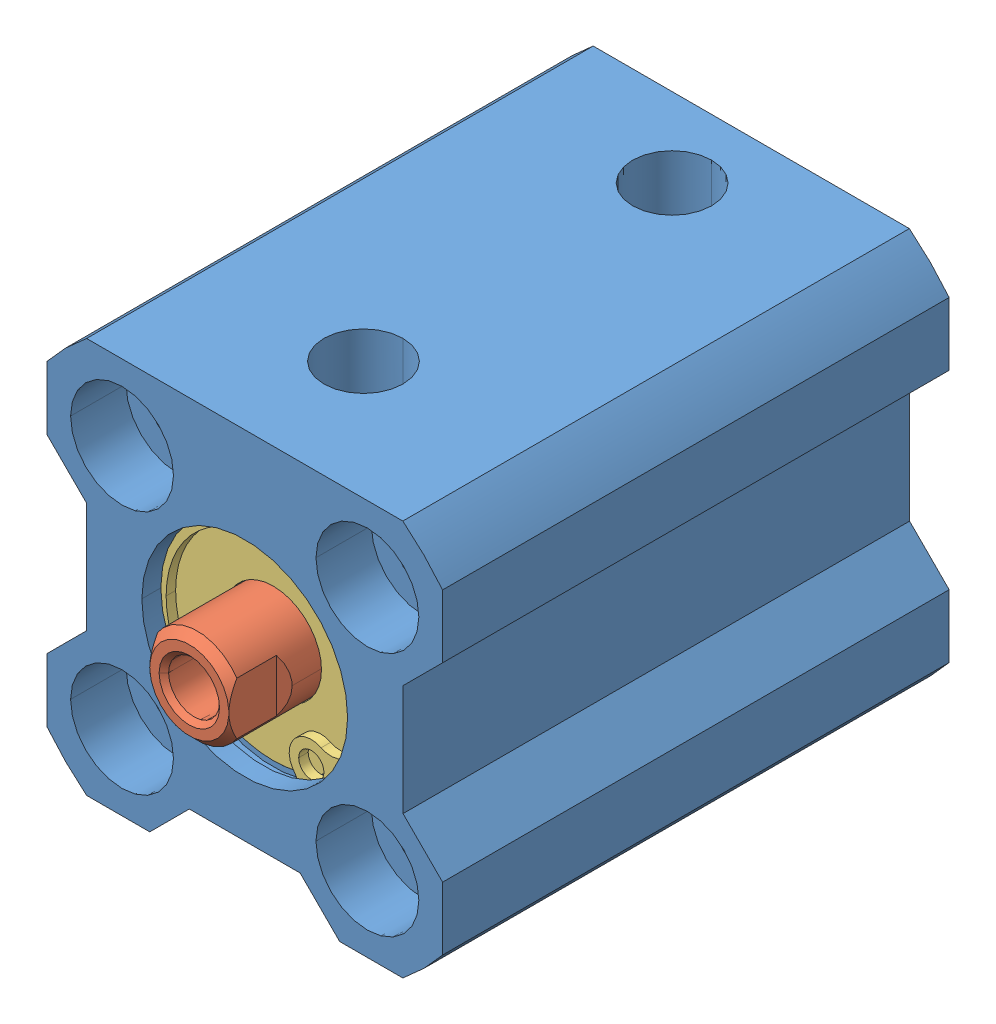
SolidWorks assembly NCQ2B12-15D, configuration Default. Lengths in mm.
Overall size (25 25 35.5).
4 component instances, 3 part files, 0 mates.
Components (placement in the parent):
- NCQ2B12-15D.STEP-1: NCQ2B12-15D.STEP [Default] at origin size (25 25 35.5)
  - NCQ2B12-15D.step_CQ2Tube_12B.STEP-1: NCQ2B12-15D.step_CQ2Tube_12B.STEP [Default] at origin size (25 25 32)
  - NCQ2B12-15D.step_CQ22031Rods_12.STEP-1: NCQ2B12-15D.step_CQ22031Rods_12.STEP [Default] at (0 0 -10) size (12 12 29.5)
  - NCQ2B12-15D.step_CQ2 SnapRing_12.STEP-1: NCQ2B12-15D.step_CQ2 SnapRing_12.STEP [Default] at (0 0 14.2) size (13.7 13.35 1.2)
